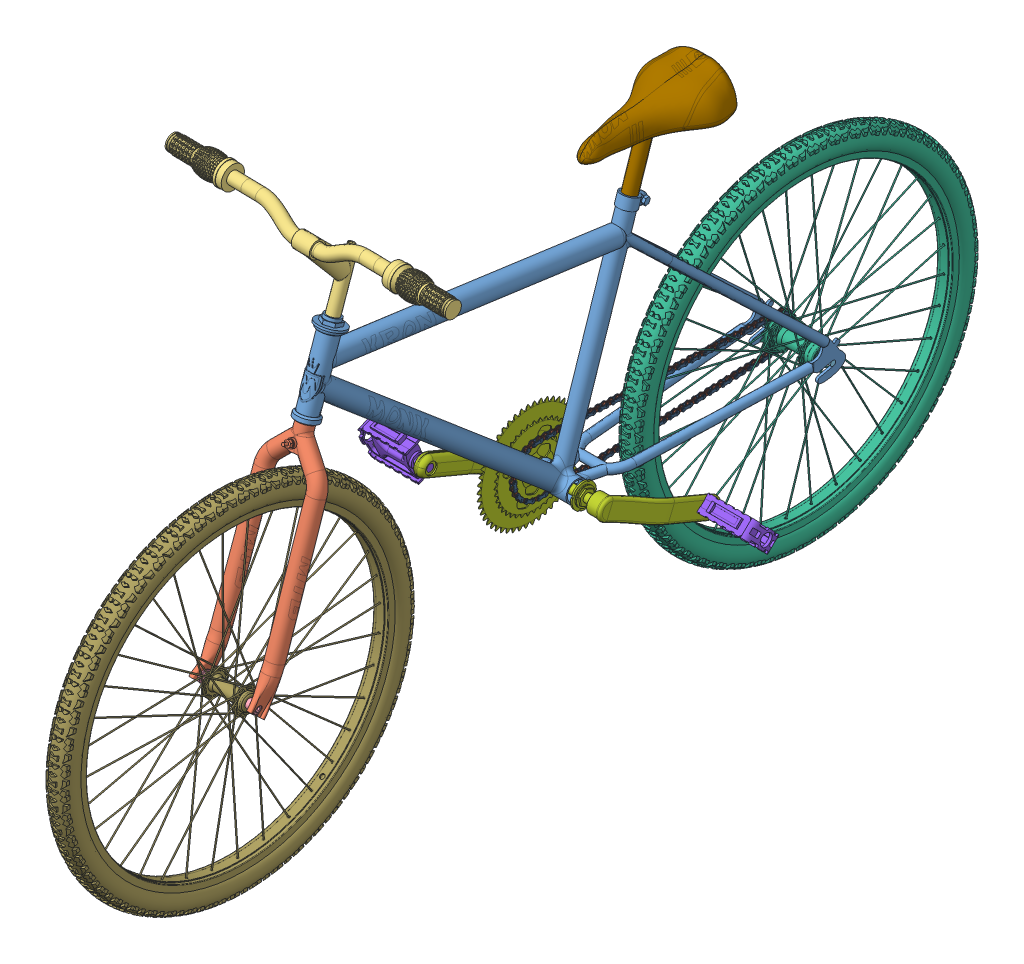
SolidWorks assembly Ensamblaje bicicleta de pruebas - Bicicleta Monk Kron R26 18 Velocidades, configuration Predeterminado. Lengths in mm.
Overall size (545.61 1133.46 1937.59).
117 component instances, 12 part files, 27 mates.
Components (placement in the parent):
- Marco - Bicicleta Monk Kron R26 18 Velocidades-1: Marco - Bicicleta Monk Kron R26 18 Velocidades [Predeterminado] at (-120.7072 88.4476 851.951) size (141.59 511.41 973.66)
- Horquilla - Bicicleta Monk Kron R26 18 Velocidades-1: Horquilla - Bicicleta Monk Kron R26 18 Velocidades [Predeterminado] at (-120.7072 49.7234 1452.2832) x (0.999532 0.010113 0.028878) z (-0.030598 0.330364 0.943357) size (134.61 452.92 50.75)
- Manubrio - Bicicleta Monk Kron R26 18 Velocidades-1: Manubrio - Bicicleta Monk Kron R26 18 Velocidades [Predeterminado] at (-120.7072 289.4957 1368.3149) x (0.999532 0.010113 0.028878) z (-0.030598 0.330364 0.943357) size (542.21 214.9 119.32)
- Eje de rotación de las ruedas - Bicicleta Monk Kron R26 18 Velocidades-3: Eje de rotación de las ruedas - Bicicleta Monk Kron R26 18 Velocidades [Predeterminado] at (-121.0511 -290.8736 1583.4642) x (0.028043 -0.680356 -0.732345) z (-0.999532 -0.010113 -0.028878) size (22 22 110)
- Pieza6^Ensamblaje bicicleta de pruebas - Bicicleta Monk Kron R26 18 Velocidades-1: Pieza6^Ensamblaje bicicleta de pruebas - Bicicleta Monk Kron R26 18 Velocidades [Predeterminado] at (-55.9572 88.4476 851.951) x (0 0 -1) z (1 0 0) size (9.5 9.5 129.5) (virtual)
- Rin y neumático trasero - Bicicleta Monk Kron R26 18 Velocidades-1: Rin y neumático trasero - Bicicleta Monk Kron R26 18 Velocidades [Predeterminado] at (-120.9572 -258.0205 516.0346) x (0 0.818982 0.57382) z (-1 0 0) size (656.36 656.26 90)
- Biela y platos - Bicicleta Monk Kron R26 18 Velocidades-1: Biela y platos - Bicicleta Monk Kron R26 18 Velocidades [Predeterminado] at (-109.7072 -257.1837 966.2576) x (1 0 0) z (0 0.387266 0.921968) size (211.33 199.67 408.06)
- Pedal - Bicicleta Monk Kron R26 18 Velocidades-1: Pedal - Bicicleta Monk Kron R26 18 Velocidades [Predeterminado] at (54.2015 -339.5482 806.2783) x (0 -0.72304 -0.690807) z (1 0 0) size (83 33.26 118.16)
- Pedal - Bicicleta Monk Kron R26 18 Velocidades-2: Pedal - Bicicleta Monk Kron R26 18 Velocidades [Predeterminado] at (-264.6158 -191.2071 1151.2843) x (0 0.924225 0.381849) z (-1 0 0) size (83 33.26 118.16)
- Asiento - Bicicleta Monk Kron R26 18 Velocidades-1: Asiento - Bicicleta Monk Kron R26 18 Velocidades [Predeterminado] at (-120.7072 240.3557 801.7122) x (1 0 0) z (0 -0.029666 0.99956) size (185.38 295.58 270.49)
- Eslabón externo de cadena - Bicicleta Monk Kron R26 18 Velocidades-1: Eslabón externo de cadena - Bicicleta Monk Kron R26 18 Velocidades [Predeterminado] at (-160.7072 -289.9045 588.8281) x (-1 0 0) z (0 -0.035902 0.999355) size (8.5 8 20.35)
- Eslabón interno de cadena - Bicicleta Monk Kron R26 18 Velocidades-1: Eslabón interno de cadena - Bicicleta Monk Kron R26 18 Velocidades [Predeterminado] at (-160.7072 -290.3479 601.1701) x (-1 0 0) z (0 -0.035902 0.999355) size (5 8 20.35)
- Eslabón interno de cadena - Bicicleta Monk Kron R26 18 Velocidades-2: Eslabón interno de cadena - Bicicleta Monk Kron R26 18 Velocidades [Predeterminado] at (-160.7072 -289.4611 576.4861) x (-1 0 0) z (0 -0.035902 0.999355) size (5 8 20.35)
- Eslabón interno de cadena - Bicicleta Monk Kron R26 18 Velocidades-3: Eslabón interno de cadena - Bicicleta Monk Kron R26 18 Velocidades [Predeterminado] at (-160.7072 -288.5743 551.802) x (-1 0 0) z (0 -0.035902 0.999355) size (5 8 20.35)
- Eslabón interno de cadena - Bicicleta Monk Kron R26 18 Velocidades-4: Eslabón interno de cadena - Bicicleta Monk Kron R26 18 Velocidades [Predeterminado] at (-160.7072 -287.6876 527.1179) x (-1 0 0) z (0 -0.035902 0.999355) size (5 8 20.35)
- Eslabón interno de cadena - Bicicleta Monk Kron R26 18 Velocidades-5: Eslabón interno de cadena - Bicicleta Monk Kron R26 18 Velocidades [Predeterminado] at (-160.7072 -283.5378 503.1387) x (-1 0 0) z (0 -0.45105 0.892499) size (5 8 20.35)
- Eslabón interno de cadena - Bicicleta Monk Kron R26 18 Velocidades-6: Eslabón interno de cadena - Bicicleta Monk Kron R26 18 Velocidades [Predeterminado] at (-160.7072 -265.1497 488.3469) x (-1 0 0) z (0 -0.968413 0.24935) size (5 8 20.35)
- Eslabón interno de cadena - Bicicleta Monk Kron R26 18 Velocidades-7: Eslabón interno de cadena - Bicicleta Monk Kron R26 18 Velocidades [Predeterminado] at (-160.7072 -241.9044 492.4189) x (-1 0 0) z (0 -0.825991 -0.563683) size (5 8 20.35)
- Eslabón interno de cadena - Bicicleta Monk Kron R26 18 Velocidades-8: Eslabón interno de cadena - Bicicleta Monk Kron R26 18 Velocidades [Predeterminado] at (-160.7072 -229.514 512.5638) x (-1 0 0) z (0 -0.14109 -0.989997) size (5 8 20.35)
- Eslabón interno de cadena - Bicicleta Monk Kron R26 18 Velocidades-9: Eslabón interno de cadena - Bicicleta Monk Kron R26 18 Velocidades [Predeterminado] at (-160.7072 -227.9089 537.1875) x (-1 0 0) z (0 -0.039616 -0.999215) size (5 8 20.35)
- Eslabón interno de cadena - Bicicleta Monk Kron R26 18 Velocidades-10: Eslabón interno de cadena - Bicicleta Monk Kron R26 18 Velocidades [Predeterminado] at (-160.7072 -226.9304 561.8681) x (-1 0 0) z (0 -0.039616 -0.999215) size (5 8 20.35)
- Eslabón interno de cadena - Bicicleta Monk Kron R26 18 Velocidades-11: Eslabón interno de cadena - Bicicleta Monk Kron R26 18 Velocidades [Predeterminado] at (-160.7072 -225.9519 586.5487) x (-1 0 0) z (0 -0.039616 -0.999215) size (5 8 20.35)
- Eslabón interno de cadena - Bicicleta Monk Kron R26 18 Velocidades-12: Eslabón interno de cadena - Bicicleta Monk Kron R26 18 Velocidades [Predeterminado] at (-160.7072 -224.9733 611.2293) x (-1 0 0) z (0 -0.039616 -0.999215) size (5 8 20.35)
- Eslabón interno de cadena - Bicicleta Monk Kron R26 18 Velocidades-13: Eslabón interno de cadena - Bicicleta Monk Kron R26 18 Velocidades [Predeterminado] at (-160.7072 -223.9948 635.9099) x (-1 0 0) z (0 -0.039616 -0.999215) size (5 8 20.35)
- Eslabón interno de cadena - Bicicleta Monk Kron R26 18 Velocidades-14: Eslabón interno de cadena - Bicicleta Monk Kron R26 18 Velocidades [Predeterminado] at (-160.7072 -223.0163 660.5905) x (-1 0 0) z (0 -0.039616 -0.999215) size (5 8 20.35)
- Eslabón interno de cadena - Bicicleta Monk Kron R26 18 Velocidades-15: Eslabón interno de cadena - Bicicleta Monk Kron R26 18 Velocidades [Predeterminado] at (-160.7072 -222.0378 685.2711) x (-1 0 0) z (0 -0.039616 -0.999215) size (5 8 20.35)
- Eslabón interno de cadena - Bicicleta Monk Kron R26 18 Velocidades-16: Eslabón interno de cadena - Bicicleta Monk Kron R26 18 Velocidades [Predeterminado] at (-160.7072 -221.0592 709.9516) x (-1 0 0) z (0 -0.039616 -0.999215) size (5 8 20.35)
- Eslabón interno de cadena - Bicicleta Monk Kron R26 18 Velocidades-17: Eslabón interno de cadena - Bicicleta Monk Kron R26 18 Velocidades [Predeterminado] at (-160.7072 -220.0807 734.6322) x (-1 0 0) z (0 -0.039616 -0.999215) size (5 8 20.35)
- Eslabón interno de cadena - Bicicleta Monk Kron R26 18 Velocidades-18: Eslabón interno de cadena - Bicicleta Monk Kron R26 18 Velocidades [Predeterminado] at (-160.7072 -219.1022 759.3128) x (-1 0 0) z (0 -0.039616 -0.999215) size (5 8 20.35)
- Eslabón interno de cadena - Bicicleta Monk Kron R26 18 Velocidades-19: Eslabón interno de cadena - Bicicleta Monk Kron R26 18 Velocidades [Predeterminado] at (-160.7072 -218.1237 783.9934) x (-1 0 0) z (0 -0.039616 -0.999215) size (5 8 20.35)
- Eslabón interno de cadena - Bicicleta Monk Kron R26 18 Velocidades-20: Eslabón interno de cadena - Bicicleta Monk Kron R26 18 Velocidades [Predeterminado] at (-160.7072 -217.1452 808.674) x (-1 0 0) z (0 -0.039616 -0.999215) size (5 8 20.35)
- Eslabón interno de cadena - Bicicleta Monk Kron R26 18 Velocidades-21: Eslabón interno de cadena - Bicicleta Monk Kron R26 18 Velocidades [Predeterminado] at (-160.7072 -216.1666 833.3546) x (-1 0 0) z (0 -0.039616 -0.999215) size (5 8 20.35)
- Eslabón interno de cadena - Bicicleta Monk Kron R26 18 Velocidades-22: Eslabón interno de cadena - Bicicleta Monk Kron R26 18 Velocidades [Predeterminado] at (-160.7072 -215.1881 858.0352) x (-1 0 0) z (0 -0.039616 -0.999215) size (5 8 20.35)
- Eslabón interno de cadena - Bicicleta Monk Kron R26 18 Velocidades-23: Eslabón interno de cadena - Bicicleta Monk Kron R26 18 Velocidades [Predeterminado] at (-160.7072 -214.2096 882.7158) x (-1 0 0) z (0 -0.039616 -0.999215) size (5 8 20.35)
- Eslabón interno de cadena - Bicicleta Monk Kron R26 18 Velocidades-24: Eslabón interno de cadena - Bicicleta Monk Kron R26 18 Velocidades [Predeterminado] at (-160.7072 -213.2311 907.3964) x (-1 0 0) z (0 -0.039616 -0.999215) size (5 8 20.35)
- Eslabón interno de cadena - Bicicleta Monk Kron R26 18 Velocidades-25: Eslabón interno de cadena - Bicicleta Monk Kron R26 18 Velocidades [Predeterminado] at (-160.7072 -212.2525 932.077) x (-1 0 0) z (0 -0.039616 -0.999215) size (5 8 20.35)
- Eslabón interno de cadena - Bicicleta Monk Kron R26 18 Velocidades-26: Eslabón interno de cadena - Bicicleta Monk Kron R26 18 Velocidades [Predeterminado] at (-160.7072 -211.274 956.7576) x (-1 0 0) z (0 -0.039616 -0.999215) size (5 8 20.35)
- Eslabón interno de cadena - Bicicleta Monk Kron R26 18 Velocidades-27: Eslabón interno de cadena - Bicicleta Monk Kron R26 18 Velocidades [Predeterminado] at (-160.7072 -213.8157 981.0951) x (-1 0 0) z (0 0.323709 -0.946157) size (5 8 20.35)
- Eslabón interno de cadena - Bicicleta Monk Kron R26 18 Velocidades-28: Eslabón interno de cadena - Bicicleta Monk Kron R26 18 Velocidades [Predeterminado] at (-160.7072 -227.4632 1001.152) x (-1 0 0) z (0 0.76129 -0.648412) size (5 8 20.35)
- Eslabón interno de cadena - Bicicleta Monk Kron R26 18 Velocidades-29: Eslabón interno de cadena - Bicicleta Monk Kron R26 18 Velocidades [Predeterminado] at (-160.7072 -249.4362 1011.434) x (-1 0 0) z (0 0.985611 -0.169027) size (5 8 20.35)
- Eslabón interno de cadena - Bicicleta Monk Kron R26 18 Velocidades-30: Eslabón interno de cadena - Bicicleta Monk Kron R26 18 Velocidades [Predeterminado] at (-160.7072 -273.5795 1009.0607) x (-1 0 0) z (0 0.933834 0.357707) size (5 8 20.35)
- Eslabón interno de cadena - Bicicleta Monk Kron R26 18 Velocidades-31: Eslabón interno de cadena - Bicicleta Monk Kron R26 18 Velocidades [Predeterminado] at (-160.7072 -293.1299 994.697) x (-1 0 0) z (0 0.620462 0.784237) size (5 8 20.35)
- Eslabón interno de cadena - Bicicleta Monk Kron R26 18 Velocidades-32: Eslabón interno de cadena - Bicicleta Monk Kron R26 18 Velocidades [Predeterminado] at (-160.7072 -302.6107 972.3666) x (-1 0 0) z (0 0.13328 0.991078) size (5 8 20.35)
- Eslabón interno de cadena - Bicicleta Monk Kron R26 18 Velocidades-33: Eslabón interno de cadena - Bicicleta Monk Kron R26 18 Velocidades [Predeterminado] at (-160.7072 -302.798 947.7326) x (-1 0 0) z (0 -0.035902 0.999355) size (5 8 20.35)
- Eslabón interno de cadena - Bicicleta Monk Kron R26 18 Velocidades-34: Eslabón interno de cadena - Bicicleta Monk Kron R26 18 Velocidades [Predeterminado] at (-160.7072 -301.9113 923.0486) x (-1 0 0) z (0 -0.035902 0.999355) size (5 8 20.35)
- Eslabón interno de cadena - Bicicleta Monk Kron R26 18 Velocidades-35: Eslabón interno de cadena - Bicicleta Monk Kron R26 18 Velocidades [Predeterminado] at (-160.7072 -301.0245 898.3645) x (-1 0 0) z (0 -0.035902 0.999355) size (5 8 20.35)
- Eslabón interno de cadena - Bicicleta Monk Kron R26 18 Velocidades-36: Eslabón interno de cadena - Bicicleta Monk Kron R26 18 Velocidades [Predeterminado] at (-160.7072 -300.1377 873.6804) x (-1 0 0) z (0 -0.035902 0.999355) size (5 8 20.35)
- Eslabón interno de cadena - Bicicleta Monk Kron R26 18 Velocidades-37: Eslabón interno de cadena - Bicicleta Monk Kron R26 18 Velocidades [Predeterminado] at (-160.7072 -299.251 848.9964) x (-1 0 0) z (0 -0.035902 0.999355) size (5 8 20.35)
- Eslabón interno de cadena - Bicicleta Monk Kron R26 18 Velocidades-38: Eslabón interno de cadena - Bicicleta Monk Kron R26 18 Velocidades [Predeterminado] at (-160.7072 -298.3642 824.3123) x (-1 0 0) z (0 -0.035902 0.999355) size (5 8 20.35)
- Eslabón interno de cadena - Bicicleta Monk Kron R26 18 Velocidades-39: Eslabón interno de cadena - Bicicleta Monk Kron R26 18 Velocidades [Predeterminado] at (-160.7072 -297.4774 799.6283) x (-1 0 0) z (0 -0.035902 0.999355) size (5 8 20.35)
- Eslabón interno de cadena - Bicicleta Monk Kron R26 18 Velocidades-40: Eslabón interno de cadena - Bicicleta Monk Kron R26 18 Velocidades [Predeterminado] at (-160.7072 -296.5907 774.9442) x (-1 0 0) z (0 -0.035902 0.999355) size (5 8 20.35)
- Eslabón interno de cadena - Bicicleta Monk Kron R26 18 Velocidades-41: Eslabón interno de cadena - Bicicleta Monk Kron R26 18 Velocidades [Predeterminado] at (-160.7072 -295.7039 750.2602) x (-1 0 0) z (0 -0.035902 0.999355) size (5 8 20.35)
- Eslabón interno de cadena - Bicicleta Monk Kron R26 18 Velocidades-42: Eslabón interno de cadena - Bicicleta Monk Kron R26 18 Velocidades [Predeterminado] at (-160.7072 -294.8171 725.5761) x (-1 0 0) z (0 -0.035902 0.999355) size (5 8 20.35)
- Eslabón interno de cadena - Bicicleta Monk Kron R26 18 Velocidades-43: Eslabón interno de cadena - Bicicleta Monk Kron R26 18 Velocidades [Predeterminado] at (-160.7072 -293.9304 700.892) x (-1 0 0) z (0 -0.035902 0.999355) size (5 8 20.35)
- Eslabón interno de cadena - Bicicleta Monk Kron R26 18 Velocidades-44: Eslabón interno de cadena - Bicicleta Monk Kron R26 18 Velocidades [Predeterminado] at (-160.7072 -293.0436 676.208) x (-1 0 0) z (0 -0.035902 0.999355) size (5 8 20.35)
- Eslabón interno de cadena - Bicicleta Monk Kron R26 18 Velocidades-45: Eslabón interno de cadena - Bicicleta Monk Kron R26 18 Velocidades [Predeterminado] at (-160.7072 -292.1568 651.5239) x (-1 0 0) z (0 -0.035902 0.999355) size (5 8 20.35)
- Eslabón interno de cadena - Bicicleta Monk Kron R26 18 Velocidades-46: Eslabón interno de cadena - Bicicleta Monk Kron R26 18 Velocidades [Predeterminado] at (-160.7072 -291.2701 626.8399) x (-1 0 0) z (0 -0.035902 0.999355) size (5 8 20.35)
- Eslabón interno de cadena - Bicicleta Monk Kron R26 18 Velocidades-47: Eslabón interno de cadena - Bicicleta Monk Kron R26 18 Velocidades [Predeterminado] at (-160.7072 -290.3833 602.1558) x (-1 0 0) z (0 -0.035902 0.999355) size (5 8 20.35)
- Eslabón interno de cadena - Bicicleta Monk Kron R26 18 Velocidades-48: Eslabón interno de cadena - Bicicleta Monk Kron R26 18 Velocidades [Predeterminado] at (-160.7072 -289.4965 577.4717) x (-1 0 0) z (0 -0.035902 0.999355) size (5 8 20.35)
- Eslabón interno de cadena - Bicicleta Monk Kron R26 18 Velocidades-49: Eslabón interno de cadena - Bicicleta Monk Kron R26 18 Velocidades [Predeterminado] at (-160.7072 -288.6098 552.7877) x (-1 0 0) z (0 -0.035902 0.999355) size (5 8 20.35)
- Eslabón interno de cadena - Bicicleta Monk Kron R26 18 Velocidades-50: Eslabón interno de cadena - Bicicleta Monk Kron R26 18 Velocidades [Predeterminado] at (-160.7072 -287.723 528.1036) x (-1 0 0) z (0 -0.035902 0.999355) size (5 8 20.35)
- Eslabón interno de cadena - Bicicleta Monk Kron R26 18 Velocidades-51: Eslabón interno de cadena - Bicicleta Monk Kron R26 18 Velocidades [Predeterminado] at (-160.7072 -283.9624 504.0158) x (-1 0 0) z (0 -0.420374 0.907351) size (5 8 20.35)
- Eslabón interno de cadena - Bicicleta Monk Kron R26 18 Velocidades-52: Eslabón interno de cadena - Bicicleta Monk Kron R26 18 Velocidades [Predeterminado] at (-160.7072 -266.089 488.6059) x (-1 0 0) z (0 -0.959354 0.282205) size (5 8 20.35)
- Eslabón interno de cadena - Bicicleta Monk Kron R26 18 Velocidades-53: Eslabón interno de cadena - Bicicleta Monk Kron R26 18 Velocidades [Predeterminado] at (-160.7072 -242.7185 491.8834) x (-1 0 0) z (0 -0.84472 -0.535208) size (5 8 20.35)
- Eslabón externo de cadena - Bicicleta Monk Kron R26 18 Velocidades-2: Eslabón externo de cadena - Bicicleta Monk Kron R26 18 Velocidades [Predeterminado] at (-160.7072 -289.0177 564.144) x (-1 0 0) z (0 -0.035902 0.999355) size (8.5 8 20.35)
- Eslabón externo de cadena - Bicicleta Monk Kron R26 18 Velocidades-3: Eslabón externo de cadena - Bicicleta Monk Kron R26 18 Velocidades [Predeterminado] at (-160.7072 -288.131 539.46) x (-1 0 0) z (0 -0.035902 0.999355) size (8.5 8 20.35)
- Eslabón externo de cadena - Bicicleta Monk Kron R26 18 Velocidades-4: Eslabón externo de cadena - Bicicleta Monk Kron R26 18 Velocidades [Predeterminado] at (-160.7072 -286.8944 514.7984) x (-1 0 0) z (0 -0.092541 0.995709) size (8.5 8 20.35)
- Eslabón externo de cadena - Bicicleta Monk Kron R26 18 Velocidades-5: Eslabón externo de cadena - Bicicleta Monk Kron R26 18 Velocidades [Predeterminado] at (-160.7072 -275.9411 493.7571) x (-1 0 0) z (0 -0.779185 0.626794) size (8.5 8 20.35)
- Eslabón externo de cadena - Bicicleta Monk Kron R26 18 Velocidades-6: Eslabón externo de cadena - Bicicleta Monk Kron R26 18 Velocidades [Predeterminado] at (-160.7072 -253.0873 487.8727) x (-1 0 0) z (0 -0.985001 -0.172547) size (8.5 8 20.35)
- Eslabón externo de cadena - Bicicleta Monk Kron R26 18 Velocidades-7: Eslabón externo de cadena - Bicicleta Monk Kron R26 18 Velocidades [Predeterminado] at (-160.7072 -233.5946 501.1751) x (-1 0 0) z (0 -0.519731 -0.85433) size (8.5 8 20.35)
- Eslabón externo de cadena - Bicicleta Monk Kron R26 18 Velocidades-8: Eslabón externo de cadena - Bicicleta Monk Kron R26 18 Velocidades [Predeterminado] at (-160.7072 -228.3982 524.8472) x (-1 0 0) z (0 -0.039616 -0.999215) size (8.5 8 20.35)
- Eslabón externo de cadena - Bicicleta Monk Kron R26 18 Velocidades-9: Eslabón externo de cadena - Bicicleta Monk Kron R26 18 Velocidades [Predeterminado] at (-160.7072 -227.4196 549.5278) x (-1 0 0) z (0 -0.039616 -0.999215) size (8.5 8 20.35)
- Eslabón externo de cadena - Bicicleta Monk Kron R26 18 Velocidades-10: Eslabón externo de cadena - Bicicleta Monk Kron R26 18 Velocidades [Predeterminado] at (-160.7072 -226.4411 574.2084) x (-1 0 0) z (0 -0.039616 -0.999215) size (8.5 8 20.35)
- Eslabón externo de cadena - Bicicleta Monk Kron R26 18 Velocidades-11: Eslabón externo de cadena - Bicicleta Monk Kron R26 18 Velocidades [Predeterminado] at (-160.7072 -225.4626 598.889) x (-1 0 0) z (0 -0.039616 -0.999215) size (8.5 8 20.35)
- Eslabón externo de cadena - Bicicleta Monk Kron R26 18 Velocidades-12: Eslabón externo de cadena - Bicicleta Monk Kron R26 18 Velocidades [Predeterminado] at (-160.7072 -224.4841 623.5696) x (-1 0 0) z (0 -0.039616 -0.999215) size (8.5 8 20.35)
- Eslabón externo de cadena - Bicicleta Monk Kron R26 18 Velocidades-13: Eslabón externo de cadena - Bicicleta Monk Kron R26 18 Velocidades [Predeterminado] at (-160.7072 -223.5055 648.2502) x (-1 0 0) z (0 -0.039616 -0.999215) size (8.5 8 20.35)
- Eslabón externo de cadena - Bicicleta Monk Kron R26 18 Velocidades-14: Eslabón externo de cadena - Bicicleta Monk Kron R26 18 Velocidades [Predeterminado] at (-160.7072 -222.527 672.9308) x (-1 0 0) z (0 -0.039616 -0.999215) size (8.5 8 20.35)
- Eslabón externo de cadena - Bicicleta Monk Kron R26 18 Velocidades-15: Eslabón externo de cadena - Bicicleta Monk Kron R26 18 Velocidades [Predeterminado] at (-160.7072 -221.5485 697.6113) x (-1 0 0) z (0 -0.039616 -0.999215) size (8.5 8 20.35)
- Eslabón externo de cadena - Bicicleta Monk Kron R26 18 Velocidades-16: Eslabón externo de cadena - Bicicleta Monk Kron R26 18 Velocidades [Predeterminado] at (-160.7072 -220.57 722.2919) x (-1 0 0) z (0 -0.039616 -0.999215) size (8.5 8 20.35)
- Eslabón externo de cadena - Bicicleta Monk Kron R26 18 Velocidades-17: Eslabón externo de cadena - Bicicleta Monk Kron R26 18 Velocidades [Predeterminado] at (-160.7072 -219.5915 746.9725) x (-1 0 0) z (0 -0.039616 -0.999215) size (8.5 8 20.35)
- Eslabón externo de cadena - Bicicleta Monk Kron R26 18 Velocidades-18: Eslabón externo de cadena - Bicicleta Monk Kron R26 18 Velocidades [Predeterminado] at (-160.7072 -218.6129 771.6531) x (-1 0 0) z (0 -0.039616 -0.999215) size (8.5 8 20.35)
- Eslabón externo de cadena - Bicicleta Monk Kron R26 18 Velocidades-19: Eslabón externo de cadena - Bicicleta Monk Kron R26 18 Velocidades [Predeterminado] at (-160.7072 -217.6344 796.3337) x (-1 0 0) z (0 -0.039616 -0.999215) size (8.5 8 20.35)
- Eslabón externo de cadena - Bicicleta Monk Kron R26 18 Velocidades-20: Eslabón externo de cadena - Bicicleta Monk Kron R26 18 Velocidades [Predeterminado] at (-160.7072 -216.6559 821.0143) x (-1 0 0) z (0 -0.039616 -0.999215) size (8.5 8 20.35)
- Eslabón externo de cadena - Bicicleta Monk Kron R26 18 Velocidades-21: Eslabón externo de cadena - Bicicleta Monk Kron R26 18 Velocidades [Predeterminado] at (-160.7072 -215.6774 845.6949) x (-1 0 0) z (0 -0.039616 -0.999215) size (8.5 8 20.35)
- Eslabón externo de cadena - Bicicleta Monk Kron R26 18 Velocidades-22: Eslabón externo de cadena - Bicicleta Monk Kron R26 18 Velocidades [Predeterminado] at (-160.7072 -214.6988 870.3755) x (-1 0 0) z (0 -0.039616 -0.999215) size (8.5 8 20.35)
- Eslabón externo de cadena - Bicicleta Monk Kron R26 18 Velocidades-23: Eslabón externo de cadena - Bicicleta Monk Kron R26 18 Velocidades [Predeterminado] at (-160.7072 -213.7203 895.0561) x (-1 0 0) z (0 -0.039616 -0.999215) size (8.5 8 20.35)
- Eslabón externo de cadena - Bicicleta Monk Kron R26 18 Velocidades-24: Eslabón externo de cadena - Bicicleta Monk Kron R26 18 Velocidades [Predeterminado] at (-160.7072 -212.7418 919.7367) x (-1 0 0) z (0 -0.039616 -0.999215) size (8.5 8 20.35)
- Eslabón externo de cadena - Bicicleta Monk Kron R26 18 Velocidades-25: Eslabón externo de cadena - Bicicleta Monk Kron R26 18 Velocidades [Predeterminado] at (-160.7072 -211.7633 944.4173) x (-1 0 0) z (0 -0.039616 -0.999215) size (8.5 8 20.35)
- Eslabón externo de cadena - Bicicleta Monk Kron R26 18 Velocidades-26: Eslabón externo de cadena - Bicicleta Monk Kron R26 18 Velocidades [Predeterminado] at (-160.7072 -211.4231 969.0901) x (-1 0 0) z (0 0.063761 -0.997965) size (8.5 8 20.35)
- Eslabón externo de cadena - Bicicleta Monk Kron R26 18 Velocidades-27: Eslabón externo de cadena - Bicicleta Monk Kron R26 18 Velocidades [Predeterminado] at (-160.7072 -219.2884 992.0428) x (-1 0 0) z (0 0.562556 -0.82676) size (8.5 8 20.35)
- Eslabón externo de cadena - Bicicleta Monk Kron R26 18 Velocidades-28: Eslabón externo de cadena - Bicicleta Monk Kron R26 18 Velocidades [Predeterminado] at (-160.7072 -237.7571 1007.7731) x (-1 0 0) z (0 0.905742 -0.423829) size (8.5 8 20.35)
- Eslabón externo de cadena - Bicicleta Monk Kron R26 18 Velocidades-29: Eslabón externo de cadena - Bicicleta Monk Kron R26 18 Velocidades [Predeterminado] at (-160.7072 -261.6677 1011.8737) x (-1 0 0) z (0 0.995203 0.097828) size (8.5 8 20.35)
- Eslabón externo de cadena - Bicicleta Monk Kron R26 18 Velocidades-30: Eslabón externo de cadena - Bicicleta Monk Kron R26 18 Velocidades [Predeterminado] at (-160.7072 -284.3223 1003.1958) x (-1 0 0) z (0 0.805879 0.59208) size (8.5 8 20.35)
- Eslabón externo de cadena - Bicicleta Monk Kron R26 18 Velocidades-31: Eslabón externo de cadena - Bicicleta Monk Kron R26 18 Velocidades [Predeterminado] at (-160.7072 -299.3745 984.1705) x (-1 0 0) z (0 0.390804 0.920474) size (8.5 8 20.35)
- Eslabón externo de cadena - Bicicleta Monk Kron R26 18 Velocidades-32: Eslabón externo de cadena - Bicicleta Monk Kron R26 18 Velocidades [Predeterminado] at (-160.7072 -303.2267 960.0752) x (-1 0 0) z (0 -0.03352 0.999438) size (8.5 8 20.35)
- Eslabón externo de cadena - Bicicleta Monk Kron R26 18 Velocidades-33: Eslabón externo de cadena - Bicicleta Monk Kron R26 18 Velocidades [Predeterminado] at (-160.7072 -302.3546 935.3906) x (-1 0 0) z (0 -0.035902 0.999355) size (8.5 8 20.35)
- Eslabón externo de cadena - Bicicleta Monk Kron R26 18 Velocidades-34: Eslabón externo de cadena - Bicicleta Monk Kron R26 18 Velocidades [Predeterminado] at (-160.7072 -301.4679 910.7065) x (-1 0 0) z (0 -0.035902 0.999355) size (8.5 8 20.35)
- Eslabón externo de cadena - Bicicleta Monk Kron R26 18 Velocidades-35: Eslabón externo de cadena - Bicicleta Monk Kron R26 18 Velocidades [Predeterminado] at (-160.7072 -300.5811 886.0225) x (-1 0 0) z (0 -0.035902 0.999355) size (8.5 8 20.35)
- Eslabón externo de cadena - Bicicleta Monk Kron R26 18 Velocidades-36: Eslabón externo de cadena - Bicicleta Monk Kron R26 18 Velocidades [Predeterminado] at (-160.7072 -299.6943 861.3384) x (-1 0 0) z (0 -0.035902 0.999355) size (8.5 8 20.35)
- Eslabón externo de cadena - Bicicleta Monk Kron R26 18 Velocidades-37: Eslabón externo de cadena - Bicicleta Monk Kron R26 18 Velocidades [Predeterminado] at (-160.7072 -298.8076 836.6544) x (-1 0 0) z (0 -0.035902 0.999355) size (8.5 8 20.35)
- Eslabón externo de cadena - Bicicleta Monk Kron R26 18 Velocidades-38: Eslabón externo de cadena - Bicicleta Monk Kron R26 18 Velocidades [Predeterminado] at (-160.7072 -297.9208 811.9703) x (-1 0 0) z (0 -0.035902 0.999355) size (8.5 8 20.35)
- Eslabón externo de cadena - Bicicleta Monk Kron R26 18 Velocidades-39: Eslabón externo de cadena - Bicicleta Monk Kron R26 18 Velocidades [Predeterminado] at (-160.7072 -297.034 787.2862) x (-1 0 0) z (0 -0.035902 0.999355) size (8.5 8 20.35)
- Eslabón externo de cadena - Bicicleta Monk Kron R26 18 Velocidades-40: Eslabón externo de cadena - Bicicleta Monk Kron R26 18 Velocidades [Predeterminado] at (-160.7072 -296.1473 762.6022) x (-1 0 0) z (0 -0.035902 0.999355) size (8.5 8 20.35)
- Eslabón externo de cadena - Bicicleta Monk Kron R26 18 Velocidades-41: Eslabón externo de cadena - Bicicleta Monk Kron R26 18 Velocidades [Predeterminado] at (-160.7072 -295.2605 737.9181) x (-1 0 0) z (0 -0.035902 0.999355) size (8.5 8 20.35)
- Eslabón externo de cadena - Bicicleta Monk Kron R26 18 Velocidades-42: Eslabón externo de cadena - Bicicleta Monk Kron R26 18 Velocidades [Predeterminado] at (-160.7072 -294.3737 713.2341) x (-1 0 0) z (0 -0.035902 0.999355) size (8.5 8 20.35)
- Eslabón externo de cadena - Bicicleta Monk Kron R26 18 Velocidades-43: Eslabón externo de cadena - Bicicleta Monk Kron R26 18 Velocidades [Predeterminado] at (-160.7072 -293.487 688.55) x (-1 0 0) z (0 -0.035902 0.999355) size (8.5 8 20.35)
- Eslabón externo de cadena - Bicicleta Monk Kron R26 18 Velocidades-44: Eslabón externo de cadena - Bicicleta Monk Kron R26 18 Velocidades [Predeterminado] at (-160.7072 -292.6002 663.8659) x (-1 0 0) z (0 -0.035902 0.999355) size (8.5 8 20.35)
- Eslabón externo de cadena - Bicicleta Monk Kron R26 18 Velocidades-45: Eslabón externo de cadena - Bicicleta Monk Kron R26 18 Velocidades [Predeterminado] at (-160.7072 -291.7134 639.1819) x (-1 0 0) z (0 -0.035902 0.999355) size (8.5 8 20.35)
- Eslabón externo de cadena - Bicicleta Monk Kron R26 18 Velocidades-46: Eslabón externo de cadena - Bicicleta Monk Kron R26 18 Velocidades [Predeterminado] at (-160.7072 -290.8267 614.4978) x (-1 0 0) z (0 -0.035902 0.999355) size (8.5 8 20.35)
- Eslabón externo de cadena - Bicicleta Monk Kron R26 18 Velocidades-47: Eslabón externo de cadena - Bicicleta Monk Kron R26 18 Velocidades [Predeterminado] at (-160.7072 -289.9399 589.8138) x (-1 0 0) z (0 -0.035902 0.999355) size (8.5 8 20.35)
- Eslabón externo de cadena - Bicicleta Monk Kron R26 18 Velocidades-48: Eslabón externo de cadena - Bicicleta Monk Kron R26 18 Velocidades [Predeterminado] at (-160.7072 -289.0531 565.1297) x (-1 0 0) z (0 -0.035902 0.999355) size (8.5 8 20.35)
- Eslabón externo de cadena - Bicicleta Monk Kron R26 18 Velocidades-49: Eslabón externo de cadena - Bicicleta Monk Kron R26 18 Velocidades [Predeterminado] at (-160.7072 -288.1664 540.4457) x (-1 0 0) z (0 -0.035902 0.999355) size (8.5 8 20.35)
- Eslabón externo de cadena - Bicicleta Monk Kron R26 18 Velocidades-50: Eslabón externo de cadena - Bicicleta Monk Kron R26 18 Velocidades [Predeterminado] at (-160.7072 -287.0297 515.7756) x (-1 0 0) z (0 -0.076363 0.99708) size (8.5 8 20.35)
- Eslabón externo de cadena - Bicicleta Monk Kron R26 18 Velocidades-51: Eslabón externo de cadena - Bicicleta Monk Kron R26 18 Velocidades [Predeterminado] at (-160.7072 -276.6898 494.3807) x (-1 0 0) z (0 -0.757373 0.652982) size (8.5 8 20.35)
- Eslabón externo de cadena - Bicicleta Monk Kron R26 18 Velocidades-52: Eslabón externo de cadena - Bicicleta Monk Kron R26 18 Velocidades [Predeterminado] at (-160.7072 -254.0498 487.7209) x (-1 0 0) z (0 -0.990309 -0.138881) size (8.5 8 20.35)
- Eslabón externo de cadena - Bicicleta Monk Kron R26 18 Velocidades-53: Eslabón externo de cadena - Bicicleta Monk Kron R26 18 Velocidades [Predeterminado] at (-160.7072 -234.1151 500.3514) x (-1 0 0) z (0 -0.548542 -0.836123) size (8.5 8 20.35)
- Rin y neumático delantero - Bicicleta Monk Kron R26 18 Velocidades-1: Rin y neumático delantero - Bicicleta Monk Kron R26 18 Velocidades [Predeterminado] at (-121.0511 -290.8736 1583.4642) x (0.000885 -0.952963 0.303085) z (0.999532 0.010113 0.028878) size (656.36 656.26 75.9)
Mates (geometry in assembly coordinates):
- Concéntrica1: concentric aligned: cylinder of Marco - Bicicleta Monk Kron R26 18 Velocidades-1 through (-120.7072 81.8126 1441.0456) axis (0 0.943799 -0.330519) radius 14.5; cylinder of Horquilla - Bicicleta Monk Kron R26 18 Velocidades-1 through (-120.7072 37.9259 1456.4147) axis (0 0.943799 -0.330519) radius 14.5
- Coincidente1: coincident anti-aligned: plane of Marco - Bicicleta Monk Kron R26 18 Velocidades-1 through (-120.7072 81.8126 1441.0456) normal (0 -0.943799 0.330519); plane of Horquilla - Bicicleta Monk Kron R26 18 Velocidades-1 through (-120.7072 81.8126 1441.0456) normal (0 0.943799 -0.330519)
- Concéntrica2: concentric aligned: cylinder of Marco - Bicicleta Monk Kron R26 18 Velocidades-1 through (-120.7072 -247.2141 1556.2708) axis (0 0.943799 -0.330519) radius 10.75; cylinder of Manubrio - Bicicleta Monk Kron R26 18 Velocidades-1 through (-120.7072 176.9476 1407.7293) axis (0 0.943799 -0.330519) radius 10.75
- Distancia1: distance = 100 mm aligned: plane of Manubrio - Bicicleta Monk Kron R26 18 Velocidades-1 through (-120.929 322.8002 1364.3298) normal (0 0.943799 -0.330519); plane of Marco - Bicicleta Monk Kron R26 18 Velocidades-1 through (-120.7072 226.0251 1390.5423) normal (0 0.943799 -0.330519)
- Coincidente3: coincident aligned: plane of Horquilla - Bicicleta Monk Kron R26 18 Velocidades-1 through (-120.7072 49.7234 1452.2832) normal (0.999532 0.010113 0.028878); plane of Manubrio - Bicicleta Monk Kron R26 18 Velocidades-1 through (-120.7072 289.4957 1368.3149) normal (0.999532 0.010113 0.028878)
- Concéntrica4: concentric anti-aligned: cylinder of Horquilla - Bicicleta Monk Kron R26 18 Velocidades-1 through (-53.7896 -290.1931 1585.4075) axis (-0.999532 -0.010113 -0.028878) radius 5; cylinder of Eje de rotación de las ruedas - Bicicleta Monk Kron R26 18 Velocidades-3 through (-62.9314 -290.2856 1585.1434) axis (0.999532 0.010113 0.028878) radius 9.5
- Ancho2: width anti-aligned: plane of Eje de rotación de las ruedas - Bicicleta Monk Kron R26 18 Velocidades-3 through (-66.1074 -292.1494 1586.7533) normal (0.999532 0.010113 0.028878); plane of Eje de rotación de las ruedas - Bicicleta Monk Kron R26 18 Velocidades-3 through (-176.0559 -293.2619 1583.5767) normal (-0.999532 -0.010113 -0.028878); plane of Horquilla - Bicicleta Monk Kron R26 18 Velocidades-1 through (-181.7918 -289.1413 1598.9868) normal (-0.999532 -0.010113 -0.028878); plane of Horquilla - Bicicleta Monk Kron R26 18 Velocidades-1 through (-61.3552 -287.9227 1602.4664) normal (-0.999532 -0.010113 -0.028878)
- Coincidente5: coincident anti-aligned: plane of Horquilla - Bicicleta Monk Kron R26 18 Velocidades-1 through (-53.7714 -300.9009 1588.5284) normal (-0.028043 0.680356 0.732345); plane of Eje de rotación de las ruedas - Bicicleta Monk Kron R26 18 Velocidades-3 through (-95.3068 -294.0163 1580.5422) normal (0.028043 -0.680356 -0.732345)
- EnPosición1: in place: plane of Marco - Bicicleta Monk Kron R26 18 Velocidades-1 through (-55.9572 -236.1802 542.0221) normal (1 0 0); plane of ? through (-55.9572 0 0) normal (1 0 0); moOrthogonalPlaneRef_w of Marco - Bicicleta Monk Kron R26 18 Velocidades-1 through (-55.9572 -236.1802 542.0221) normal (1 0 0); plane of ? through (-55.9572 0 0) normal (0 1 0); plane of Marco - Bicicleta Monk Kron R26 18 Velocidades-1 through (-55.9572 -236.1802 542.0221) normal (1 0 0); plane of ? through (-55.9572 0 0) normal (0 0 -1); plane of Marco - Bicicleta Monk Kron R26 18 Velocidades-1 through (-55.9572 -236.1802 542.0221) normal (1 0 0); unknown of Pieza6^Ensamblaje bicicleta de pruebas - Bicicleta Monk Kron R26 18 Velocidades-1
- Coincidente6: coincident aligned: plane of Marco - Bicicleta Monk Kron R26 18 Velocidades-1 through (-55.9572 -236.1802 542.0221) normal (1 0 0); plane of Pieza6^Ensamblaje bicicleta de pruebas - Bicicleta Monk Kron R26 18 Velocidades-1 through (-55.9572 88.4476 851.951) normal (1 0 0)
- Coincidente7: coincident aligned: moOrthogonalPlaneRef_w of Marco - Bicicleta Monk Kron R26 18 Velocidades-1 through (-55.9572 88.4476 851.951) normal (0 1 0); plane of Pieza6^Ensamblaje bicicleta de pruebas - Bicicleta Monk Kron R26 18 Velocidades-1 through (-55.9572 88.4476 851.951) normal (0 1 0)
- Coincidente8: coincident anti-aligned: moOrthogonalPlaneRef_w of Marco - Bicicleta Monk Kron R26 18 Velocidades-1 through (-55.9572 88.4476 851.951) normal (0 0 1); plane of Pieza6^Ensamblaje bicicleta de pruebas - Bicicleta Monk Kron R26 18 Velocidades-1 through (-55.9572 88.4476 851.951) normal (0 0 -1)
- Ancho3: width anti-aligned: plane of Pieza6^Ensamblaje bicicleta de pruebas - Bicicleta Monk Kron R26 18 Velocidades-1 through (-185.4572 -236.1802 542.0221) normal (-1 0 0); plane of Pieza6^Ensamblaje bicicleta de pruebas - Bicicleta Monk Kron R26 18 Velocidades-1 through (-55.9572 -258.0205 516.0346) normal (1 0 0); plane of Marco - Bicicleta Monk Kron R26 18 Velocidades-1 through (-55.9572 -236.1802 542.0221) normal (1 0 0); plane of Marco - Bicicleta Monk Kron R26 18 Velocidades-1 through (-185.4572 -236.1802 542.0221) normal (-1 0 0)
- Concéntrica5: concentric anti-aligned: cylinder of Pieza6^Ensamblaje bicicleta de pruebas - Bicicleta Monk Kron R26 18 Velocidades-1 through (-198.8922 -258.0205 516.0346) axis (1 0 0) radius 4.75; cylinder of Rin y neumático trasero - Bicicleta Monk Kron R26 18 Velocidades-1 through (-188.0275 -258.0205 516.0346) axis (-1 0 0) radius 8.5
- Ancho4: width aligned: plane of Rin y neumático trasero - Bicicleta Monk Kron R26 18 Velocidades-1 through (-76.7072 -249.4132 503.7499) normal (1 0 0); plane of Rin y neumático trasero - Bicicleta Monk Kron R26 18 Velocidades-1 through (-164.7072 -248.8968 503.0128) normal (-1 0 0); plane of Pieza6^Ensamblaje bicicleta de pruebas - Bicicleta Monk Kron R26 18 Velocidades-1 through (-55.9572 -258.0205 516.0346) normal (1 0 0); plane of Pieza6^Ensamblaje bicicleta de pruebas - Bicicleta Monk Kron R26 18 Velocidades-1 through (-185.4572 -236.1802 542.0221) normal (-1 0 0)
- Concéntrica6: concentric aligned: cylinder of Marco - Bicicleta Monk Kron R26 18 Velocidades-1 through (-87.2072 -257.1837 966.2576) axis (-1 0 0) radius 17.5; cylinder of Biela y platos - Bicicleta Monk Kron R26 18 Velocidades-1 through (-185.7072 -257.1837 966.2576) axis (-1 0 0) radius 7.85
- Coincidente9: coincident aligned: plane of Rin y neumático trasero - Bicicleta Monk Kron R26 18 Velocidades-1 through (-159.7072 -239.0845 489.0082) normal (1 0 0); plane of Biela y platos - Bicicleta Monk Kron R26 18 Velocidades-1 through (-159.7072 -229.5247 954.6396) normal (1 0 0)
- Concéntrica8: concentric aligned: cylinder of Biela y platos - Bicicleta Monk Kron R26 18 Velocidades-1 through (-185.7082 -329.0134 795.2519) axis (1 0 0) radius 6.5; cylinder of Pedal - Bicicleta Monk Kron R26 18 Velocidades-1 through (-18.7985 -329.0134 795.2519) axis (1 0 0) radius 6.5
- Coincidente10: coincident aligned: plane of Biela y platos - Bicicleta Monk Kron R26 18 Velocidades-1 through (-18.7985 -329.0134 795.2519) normal (-1 0 0); plane of Pedal - Bicicleta Monk Kron R26 18 Velocidades-1 through (-18.7985 -329.0134 795.2519) normal (-1 0 0)
- Concéntrica9: concentric aligned: cylinder of Biela y platos - Bicicleta Monk Kron R26 18 Velocidades-1 through (-24.7062 -185.3839 1137.1899) axis (-1 0 0) radius 6.5; cylinder of Pedal - Bicicleta Monk Kron R26 18 Velocidades-2 through (-191.6158 -185.3839 1137.1899) axis (-1 0 0) radius 6.5
- Coincidente11: coincident aligned: plane of Biela y platos - Bicicleta Monk Kron R26 18 Velocidades-1 through (-191.6158 -185.3839 1137.1899) normal (1 0 0); plane of Pedal - Bicicleta Monk Kron R26 18 Velocidades-2 through (-191.6158 -185.3839 1137.1899) normal (1 0 0)
- Concéntrica10: concentric anti-aligned: cylinder of Marco - Bicicleta Monk Kron R26 18 Velocidades-1 through (-120.7072 145.4131 833.1114) axis (0 -0.949425 0.313992) radius 12; cylinder of Asiento - Bicicleta Monk Kron R26 18 Velocidades-1 through (-120.7072 21.9878 873.9304) axis (0 0.949425 -0.313992) radius 12
- Distancia4: distance = 100 mm anti-aligned: plane of Asiento - Bicicleta Monk Kron R26 18 Velocidades-1 through (-120.7072 240.3557 801.7122) normal (0 -0.949425 0.313992); plane of Marco - Bicicleta Monk Kron R26 18 Velocidades-1 through (-120.7072 145.4131 833.1114) normal (0 0.949425 -0.313992)
- Coincidente14: coincident aligned: plane of Marco - Bicicleta Monk Kron R26 18 Velocidades-1 through (-120.7072 88.4476 851.951) normal (1 0 0); plane of Asiento - Bicicleta Monk Kron R26 18 Velocidades-1 through (-120.7072 240.3557 801.7122) normal (1 0 0)
- Relación de posición de engranaje2: gear = 100 : 33 mm: circle of Rin y neumático trasero - Bicicleta Monk Kron R26 18 Velocidades-1; circle of Biela y platos - Bicicleta Monk Kron R26 18 Velocidades-1
- Concéntrica11: concentric anti-aligned: cylinder of Eje de rotación de las ruedas - Bicicleta Monk Kron R26 18 Velocidades-3 through (-179.1708 -291.4617 1581.785) axis (-0.999532 -0.010113 -0.028878) radius 8.5; cylinder of Rin y neumático delantero - Bicicleta Monk Kron R26 18 Velocidades-1 through (-54.0122 -290.1953 1585.4011) axis (0.999532 0.010113 0.028878) radius 8.5
- Ancho5: width anti-aligned: plane of Rin y neumático delantero - Bicicleta Monk Kron R26 18 Velocidades-1 through (-82.7931 -293.7159 1574.4157) normal (0.999532 0.010113 0.028878); plane of Eje de rotación de las ruedas - Bicicleta Monk Kron R26 18 Velocidades-3 through (-158.6576 -294.4835 1572.2238) normal (-0.999532 -0.010113 -0.028878); plane of Rin y neumático delantero - Bicicleta Monk Kron R26 18 Velocidades-1 through (-176.0559 -293.2619 1583.5767) normal (-0.999532 -0.010113 -0.028878); plane of Eje de rotación de las ruedas - Bicicleta Monk Kron R26 18 Velocidades-3 through (-66.1074 -292.1494 1586.7533) normal (0.999532 0.010113 0.028878)
